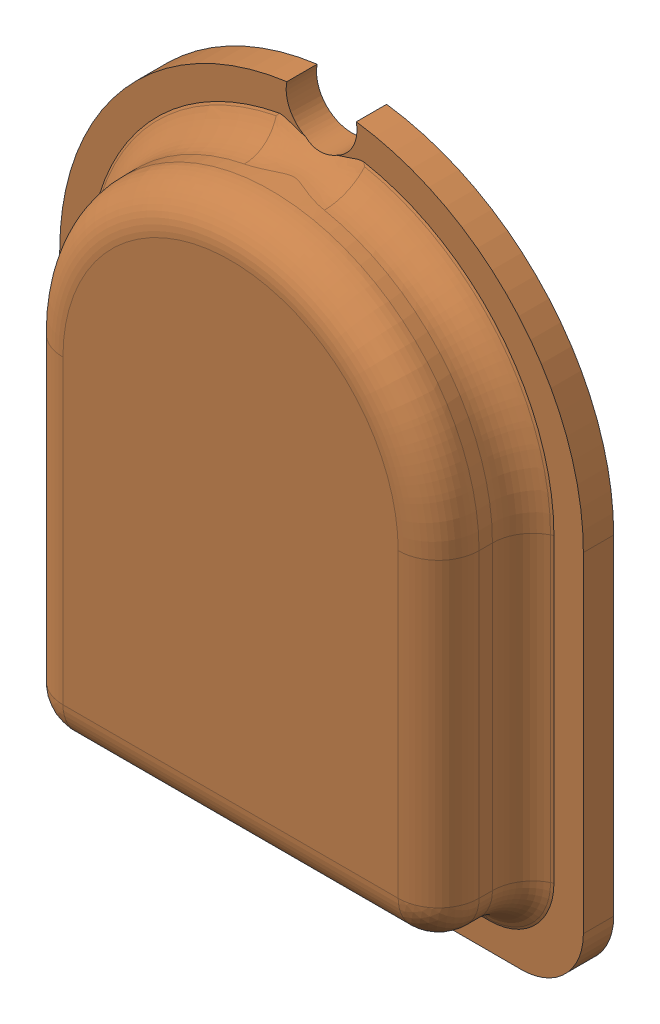
SolidWorks assembly new, configuration 默认. Lengths in mm.
Overall size (25.9 32.24 6).
2 component instances, 2 part files, 0 mates.
Components (placement in the parent):
- Skin0.2-1: Skin0.2 [默认] at (-119.2503 39.3851 -2.6) size (23.9 30.06 5.2)
- Skin1-1: Skin1 [默认] at (-119.2503 39.3851 -2.6) size (25.9 32.24 6)
